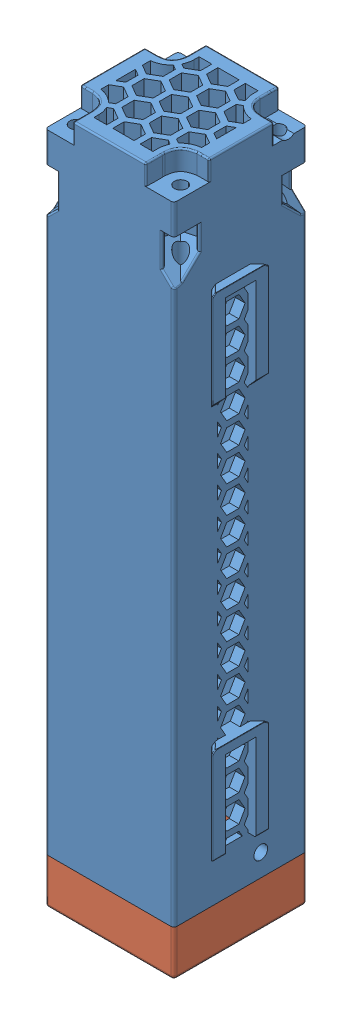
SolidWorks assembly Center, configuration Standard. Lengths in mm.
Overall size (48.78 228.56 43.91).
2 component instances, 2 part files, 6 mates.
Components (placement in the parent):
- Center-1: Center [Standard] at (55.0369 -294.7118 21.21) size (48.78 213.35 43.91)
- Center Cap-1: Center Cap [Standard] at (55.0369 -294.7118 21.21) size (42.4 15.21 43.8)
Mates (geometry in assembly coordinates):
- Deckungsgleich1: coincident anti-aligned: plane of Center-1 through (0 246.1118 -43.6) normal (-1 0 0); plane of Center Cap-1 through (0 124.785 -43.6) normal (1 0 0)
- Deckungsgleich2: coincident anti-aligned: plane of Center-1 through (37.4 232.1118 0) normal (0 0 -1); plane of Center Cap-1 through (37.4 110.785 0) normal (0 0 1)
- Deckungsgleich3: coincident aligned: plane of Center-1 through (-21.2 81.4118 -21.9) normal (0 1 0); plane of Center Cap-1 through (-21.2 81.4118 -21.9) normal (0 1 0)
- Deckungsgleich4: coincident anti-aligned: plane of ? through (37.4 -62.6 0) normal (0 0 -1)
- Deckungsgleich5: coincident anti-aligned: plane of ? through (0 -48.6 -43.6) normal (-1 0 0)
- Deckungsgleich6: coincident anti-aligned: plane of ? through (-2.2 0 -42.8) normal (0 -1 0)
